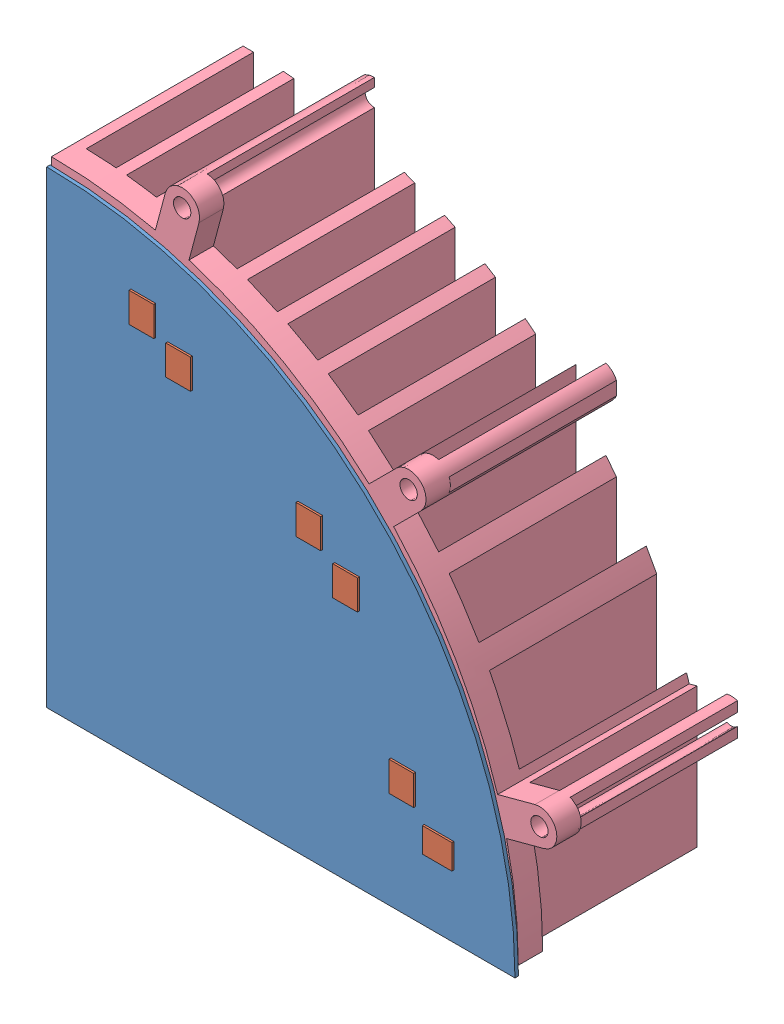
SolidWorks assembly A21112018, configuration Default. Lengths in mm.
Overall size (145.06 146.68 57.56).
11 component instances, 4 part files, 10 mates.
Components (placement in the parent):
- PCB-1: PCB [Default] at (161.8519 348.1938 87.9111) size (134.41 134.41 1)
- Gan-1: Gan [Default] at (98.9061 50.2567 89.4711) x (0 1 0) z (-1 0 0) size (8.5 0.56 7.1)
- Gan-2: Gan [Default] at (82.7784 90.7768 89.4711) x (0 1 0) z (-1 0 0) size (8.5 0.56 7.1)
- Gan-3: Gan [Default] at (72.2195 100.7465 89.4711) x (0 1 0) z (-1 0 0) size (8.5 0.56 7.1)
- Gan-8: Gan [Default] at (34.85 121.6821 89.4711) x (0 1 0) z (-1 0 0) size (8.5 0.56 7.1)
- Gan-10: Gan [Default] at (105.6232 35.9272 89.4711) x (-1 0 0) z (0 -1 0) size (8.5 0.56 7.1)
- Gan-11: Gan [Default] at (24.0694 122.6242 89.4711) x (0 -1 0) z (1 0 0) size (8.5 0.56 7.1)
- termal_macun-4: termal_macun [Default] at (110.6136 37.9219 86.9111) x (1 0 0) z (0 -1 0) size (25 1 25)
- termal_macun-5: termal_macun [Default] at (84.9442 88.0521 86.9111) x (1 0 0) z (0 -1 0) size (25 1 25)
- termal_macun-6: termal_macun [Default] at (37.9567 118.2828 86.9111) x (1 0 0) z (0 -1 0) size (25 1 25)
- Heat_sink_materialli-1: Heat_sink_materialli [Default] at (160.8089 349.8193 86.9111) x (-1 0 0) z (0 -1 0) size (145.06 55 145.06)
Mates (geometry in assembly coordinates):
- Coincident7: coincident anti-aligned: plane of PCB-1 through (-3.5565 14.1938 88.9111) normal (0 0 1); plane of Gan-1 through (98.9061 50.2567 88.9111) normal (0 0 -1)
- Coincident8: coincident anti-aligned: plane of PCB-1 through (-3.5565 14.1938 88.9111) normal (0 0 1); plane of Gan-2 through (82.7784 90.7768 88.9111) normal (0 0 -1)
- Coincident9: coincident anti-aligned: plane of PCB-1 through (-3.5565 14.1938 88.9111) normal (0 0 1); plane of Gan-8 through (34.85 121.6821 88.9111) normal (0 0 -1)
- Coincident10: coincident anti-aligned: plane of PCB-1 through (-3.5565 14.1938 88.9111) normal (0 0 1); plane of Gan-3 through (72.2195 100.7465 88.9111) normal (0 0 -1)
- Coincident12: coincident anti-aligned: plane of PCB-1 through (-3.5565 14.1938 88.9111) normal (0 0 1); plane of Gan-10 through (105.6232 35.9272 88.9111) normal (0 0 -1)
- Coincident13: coincident anti-aligned: plane of PCB-1 through (-3.5565 14.1938 88.9111) normal (0 0 1); plane of Gan-11 through (24.0694 122.6242 88.9111) normal (0 0 -1)
- Coincident14: coincident anti-aligned: plane of PCB-1 through (-3.5565 14.1938 87.9111) normal (0 0 -1); plane of termal_macun-4 through (110.6136 37.9219 87.9111) normal (0 0 1)
- Coincident15: coincident anti-aligned: plane of PCB-1 through (-3.5565 14.1938 87.9111) normal (0 0 -1); plane of termal_macun-5 through (84.9442 88.0521 87.9111) normal (0 0 1)
- Coincident16: coincident anti-aligned: plane of PCB-1 through (-3.5565 14.1938 87.9111) normal (0 0 -1); plane of termal_macun-6 through (37.9567 118.2828 87.9111) normal (0 0 1)
- Coincident17: coincident aligned: plane of termal_macun-5 through (84.9442 88.0521 86.9111) normal (0 0 -1); circle of Heat_sink_materialli-1
